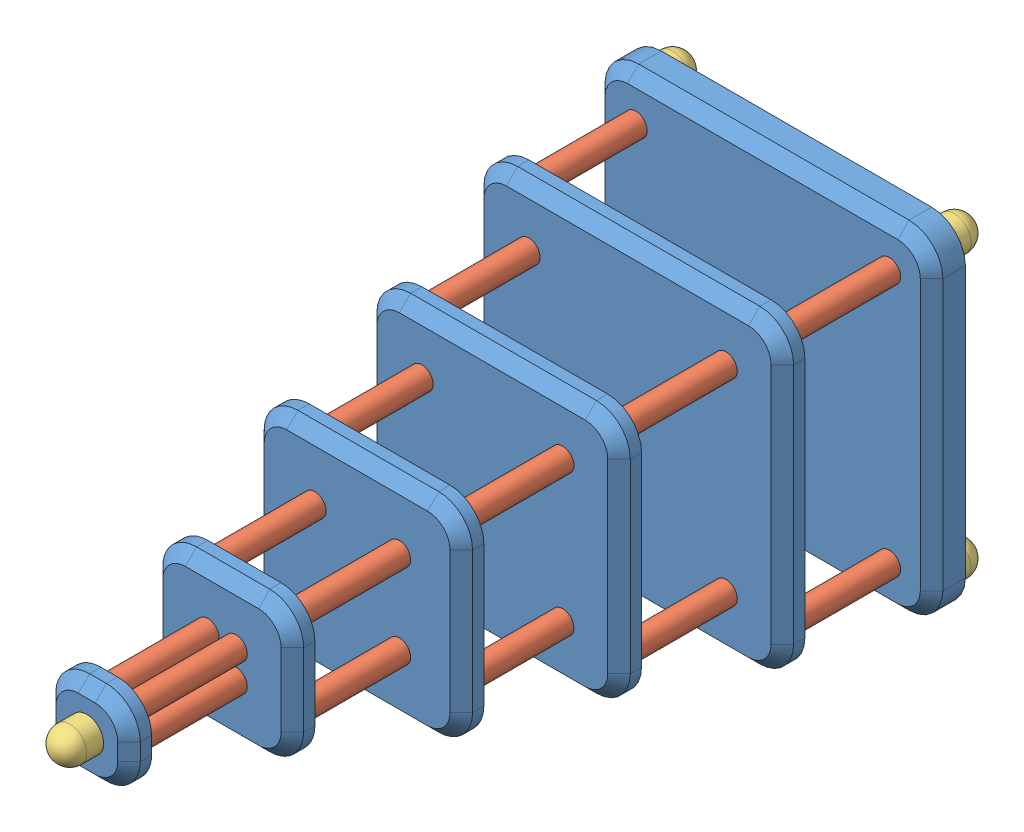
SolidWorks assembly E57, configuration Predeterminado. Lengths in mm.
Overall size (300 300 690).
31 component instances, 3 part files, 30 mates.
Components (placement in the parent):
- P57-1: P57 [Configuracion 1] at origin size (300 300 30)
- P57-2: P57 [Configuracion 2] at (0 0 130) size (275 275 20)
- P57-3: P57 [Configuracion 3] at (0 0 250) size (225 225 20)
- P57-4: P57 [Configuracion 4] at (0 0 370) size (185 185 20)
- P57-5: P57 [Configuracion 5] at (0 0 490) size (125 125 20)
- P57-6: P57 [Configuracion 6] at (0 0 610) size (75 75 20)
- P57.2-8: P57.2 [Predeterminado] at (112.5 112.5 80) x (0.999998 -0.00217 0) z (0.00217 0.999998 0) size (20 120 20)
- P57.2-9: P57.2 [Predeterminado] at (-112.5 112.5 80) x (0.999998 -0.00217 0) z (0.00217 0.999998 0) size (20 120 20)
- P57.2-10: P57.2 [Predeterminado] at (112.5 -112.5 80) x (0.999998 -0.00217 0) z (0.00217 0.999998 0) size (20 120 20)
- P57.2-11: P57.2 [Predeterminado] at (-112.5 -112.5 80) x (0.999998 -0.00217 0) z (0.00217 0.999998 0) size (20 120 20)
- P57.2-12: P57.2 [Predeterminado] at (87.5 87.5 200) x (0.60488 -0.796316 0) z (0.796316 0.60488 0) size (20 120 20)
- P57.2-13: P57.2 [Predeterminado] at (-87.5 87.5 200) x (0.60488 -0.796316 0) z (0.796316 0.60488 0) size (20 120 20)
- P57.2-14: P57.2 [Predeterminado] at (87.5 -87.5 200) x (0.60488 -0.796316 0) z (0.796316 0.60488 0) size (20 120 20)
- P57.2-15: P57.2 [Predeterminado] at (-87.5 -87.5 200) x (0.60488 -0.796316 0) z (0.796316 0.60488 0) size (20 120 20)
- P57.2-16: P57.2 [Predeterminado] at (37.5 37.5 440) x (1 0 0) z (0 1 0) size (20 120 20)
- P57.2-17: P57.2 [Predeterminado] at (12.5 12.5 560) x (1 0 0) z (0 1 0) size (20 120 20)
- P57.2-18: P57.2 [Predeterminado] at (62.5 62.5 320) x (1 0 0) z (0 1 0) size (20 120 20)
- P57.2-19: P57.2 [Predeterminado] at (-62.5 62.5 320) x (1 0 0) z (0 1 0) size (20 120 20)
- P57.2-20: P57.2 [Predeterminado] at (62.5 -62.5 320) x (1 0 0) z (0 1 0) size (20 120 20)
- P57.2-21: P57.2 [Predeterminado] at (-62.5 -62.5 320) x (1 0 0) z (0 1 0) size (20 120 20)
- P57.2-22: P57.2 [Predeterminado] at (-37.5 37.5 440) x (1 0 0) z (0 1 0) size (20 120 20)
- P57.2-23: P57.2 [Predeterminado] at (37.5 -37.5 440) x (1 0 0) z (0 1 0) size (20 120 20)
- P57.2-24: P57.2 [Predeterminado] at (-37.5 -37.5 440) x (1 0 0) z (0 1 0) size (20 120 20)
- P57.2-25: P57.2 [Predeterminado] at (-12.5 12.5 560) x (1 0 0) z (0 1 0) size (20 120 20)
- P57.2-26: P57.2 [Predeterminado] at (12.5 -12.5 560) x (1 0 0) z (0 1 0) size (20 120 20)
- P57.2-27: P57.2 [Predeterminado] at (-12.5 -12.5 560) x (1 0 0) z (0 1 0) size (20 120 20)
- P57.3-1: P57.3 [Predeterminado] at (0 0 620) x (-0.700667 -0.713489 0) z (-0.713489 0.700667 0) size (30 40 30)
- P57.3-2: P57.3 [Predeterminado] at (-125 -125 10) x (-0.611044 -0.791597 0) z (0.791597 -0.611044 0) size (30 40 30)
- P57.3-3: P57.3 [Predeterminado] at (-125 125 10) x (-0.611044 -0.791597 0) z (0.791597 -0.611044 0) size (30 40 30)
- P57.3-4: P57.3 [Predeterminado] at (125 -125 10) x (-0.611044 -0.791597 0) z (0.791597 -0.611044 0) size (30 40 30)
- P57.3-5: P57.3 [Predeterminado] at (125 125 10) x (-0.611044 -0.791597 0) z (0.791597 -0.611044 0) size (30 40 30)
Mates (geometry in assembly coordinates):
- Coincidente1: coordinate: point of P57-1
- Concéntrica1: concentric anti-aligned: cylinder of P57-1 through (112.5 112.5 30) axis (0 0 1) radius 6; cylinder of P57.2-8 through (112.5 112.5 20) axis (0 0 -1) radius 6
- Concéntrica3: concentric anti-aligned: cone of P57-2 through (112.5 112.5 140) axis (0 0 1); cylinder of P57.2-8 through (112.5 112.5 20) axis (0 0 -1) radius 6
- Coincidente2: coincident anti-aligned: plane of P57-2 through (-107.5 -107.5 130) normal (0 0 -1); plane of P57.2-8 through (112.513 118.5 130) normal (0 0 1)
- Coincidente3: coincident anti-aligned: plane of P57-1 through (-120 -120 30) normal (0 0 1); plane of P57.2-8 through (112.5217 122.5 30) normal (0 0 -1)
- Coincidente4: coincident aligned: circle of P57-2; cylinder of P57.2-11 through (-112.5 -112.5 20) axis (0 0 -1) radius 6
- Concéntrica4: concentric anti-aligned: cylinder of P57-2 through (87.5 87.5 150) axis (0 0 1) radius 6; cylinder of P57.2-12 through (87.5 87.5 140) axis (0 0 -1) radius 6
- Coincidente5: coincident anti-aligned: circle of P57-2; plane of P57.2-12 through (92.2779 91.1293 140) normal (0 0 -1)
- Concéntrica5: concentric anti-aligned: cylinder of P57-4 through (37.5 37.5 390) axis (0 0 1) radius 6; cylinder of P57.2-16 through (37.5 37.5 380) axis (0 0 -1) radius 6
- Coincidente6: coincident anti-aligned: plane of P57-4 through (-62.5 -62.5 390) normal (0 0 1); plane of P57.2-16 through (37.5 47.5 390) normal (0 0 -1)
- Concéntrica6: concentric anti-aligned: cylinder of P57-3 through (62.5 62.5 270) axis (0 0 1) radius 6; cylinder of P57.2-18 through (62.5 62.5 260) axis (0 0 -1) radius 6
- Coincidente7: coincident anti-aligned: plane of P57-3 through (-82.5 -82.5 270) normal (0 0 1); plane of P57.2-18 through (62.5 72.5 270) normal (0 0 -1)
- Concéntrica7: concentric anti-aligned: cylinder of P57-5 through (12.5 12.5 510) axis (0 0 1) radius 6; cylinder of P57.2-17 through (12.5 12.5 500) axis (0 0 -1) radius 6
- Coincidente8: coincident anti-aligned: plane of P57-5 through (-32.5 -32.5 510) normal (0 0 1); plane of P57.2-17 through (12.5 22.5 510) normal (0 0 -1)
- Coincidente9: coincident aligned: circle of P57-3; cylinder of P57.2-12 through (87.5 87.5 140) axis (0 0 -1) radius 6
- Coincidente10: coincident anti-aligned: plane of P57-3 through (-82.5 -82.5 250) normal (0 0 -1); plane of P57.2-12 through (92.2779 91.1293 250) normal (0 0 1)
- Concéntrica8: concentric aligned: cylinder of P57-3 through (-87.5 -87.5 250) axis (0 0 -1) radius 6; cylinder of P57.2-15 through (-87.5 -87.5 140) axis (0 0 -1) radius 6
- Concéntrica9: concentric aligned: cylinder of P57-4 through (62.5 62.5 370) axis (0 0 -1) radius 6; cylinder of P57.2-18 through (62.5 62.5 260) axis (0 0 -1) radius 6
- Coincidente12: coincident anti-aligned: plane of P57-4 through (-62.5 -62.5 370) normal (0 0 -1); plane of P57.2-18 through (62.5 68.5 370) normal (0 0 1)
- Concéntrica10: concentric aligned: cylinder of P57-5 through (37.5 37.5 490) axis (0 0 -1) radius 6; cylinder of P57.2-16 through (37.5 37.5 380) axis (0 0 -1) radius 6
- Coincidente13: coincident anti-aligned: plane of P57-5 through (-32.5 -32.5 490) normal (0 0 -1); plane of P57.2-16 through (37.5 43.5 490) normal (0 0 1)
- Concéntrica11: concentric aligned: cylinder of P57-6 through (12.5 12.5 610) axis (0 0 -1) radius 6; cylinder of P57.2-17 through (12.5 12.5 500) axis (0 0 -1) radius 6
- Coincidente14: coincident aligned: plane of P57-6 through (-7.5 -7.5 610) normal (0 0 -1); circle of P57.2-17
- Concéntrica12: concentric aligned: cylinder of P57-4 through (-62.5 -62.5 370) axis (0 0 -1) radius 6; cylinder of P57.2-21 through (-62.5 -62.5 260) axis (0 0 -1) radius 6
- Concéntrica13: concentric aligned: cylinder of P57-5 through (-37.5 -37.5 490) axis (0 0 -1) radius 6; cylinder of P57.2-24 through (-37.5 -37.5 380) axis (0 0 -1) radius 6
- Concéntrica14: concentric aligned: cylinder of P57-6 through (-12.5 -12.5 610) axis (0 0 -1) radius 6; cylinder of P57.2-27 through (-12.5 -12.5 500) axis (0 0 -1) radius 6
- Concéntrica16: concentric aligned: cylinder of P57-6 through (0 0 630) axis (0 0 1) radius 6; cylinder of P57.3-1 through (0 0 660) axis (0 0 1) radius 6
- Coincidente16: coincident anti-aligned: plane of P57-6 through (-7.5 -7.5 630) normal (0 0 1); plane of P57.3-1 through (4.204 4.2809 630) normal (0 0 -1)
- Concéntrica17: concentric aligned: cylinder of P57-1 through (-125 -125 0) axis (0 0 -1) radius 6; cylinder of P57.3-2 through (-125 -125 -30) axis (0 0 -1) radius 6
- Coincidente17: coincident anti-aligned: plane of P57-1 through (-120 -120 0) normal (0 0 -1); plane of P57.3-2 through (-121.3337 -120.2504 0) normal (0 0 1)
